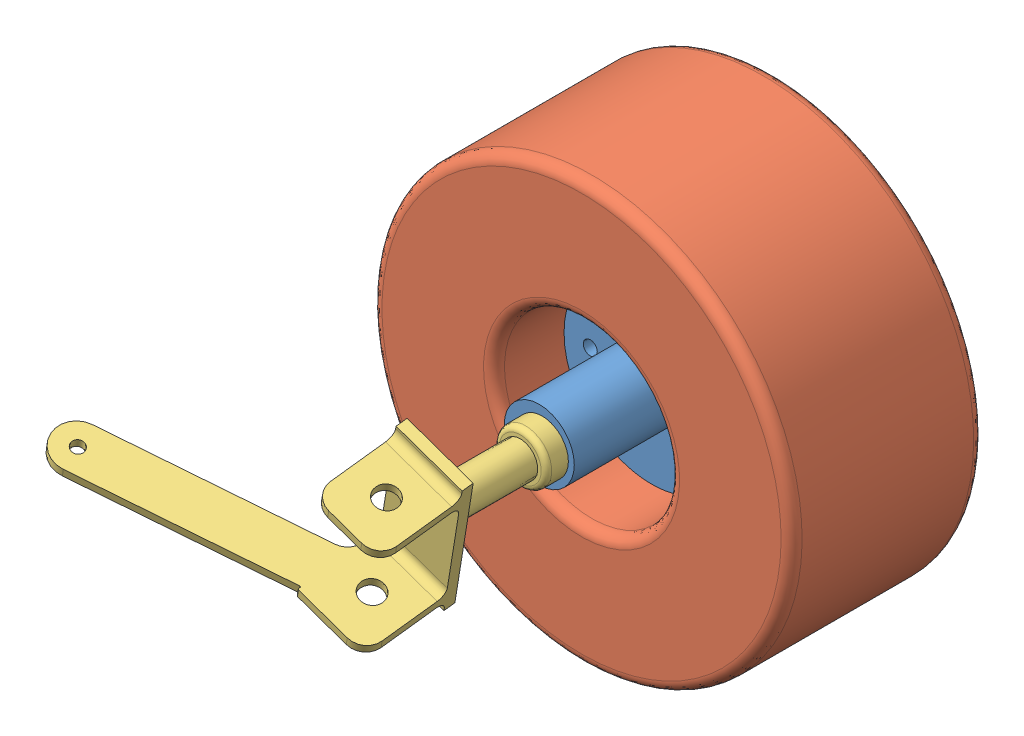
SolidWorks assembly Assem1, configuration Default. Lengths in mm.
Overall size (368.83 368.83 290.62).
3 component instances, 3 part files, 5 mates.
Components (placement in the parent):
- rear hubs and wheels-1: rear hubs and wheels [Default] at (-8.5252 65.0084 65.9926) size (100 100 72.5)
- wheels-1: wheels [Default] at (-8.5252 65.0084 -4.0074) x (0.5 -0.866025 0) z (0 0 1) size (270 270 110)
- left stub axle-1: left stub axle [Default] at (-8.5252 65.0084 191.9926) x (-0.068801 -0.196198 0.978148) z (-0.94366 0.330916 0) size (244.05 90 159.36)
Mates (geometry in assembly coordinates):
- Concentric4: concentric aligned: circle of rear hubs and wheels-1; circle of wheels-1
- Coincident4: coincident aligned: circle of rear hubs and wheels-1; circle of wheels-1
- Parallel3: parallel anti-aligned: plane of rear hubs and wheels-1 through (-8.5252 65.0084 128.4926) normal (0 0 1); plane of left stub axle-1 through (-8.5252 65.0084 32.9926) normal (0 0 -1)
- Concentric8: concentric aligned: cylinder of rear hubs and wheels-1 through (-8.5252 65.0084 55.9926) axis (0 0 1) radius 6.5; cylinder of left stub axle-1 through (-8.5252 65.0084 32.9926) axis (0 0 1) radius 6.5
- Coincident7: coincident anti-aligned: plane of rear hubs and wheels-1 through (-8.5252 65.0084 115.9926) normal (0 0 1); plane of left stub axle-1 through (-8.5252 65.0084 115.9926) normal (0 0 -1)
